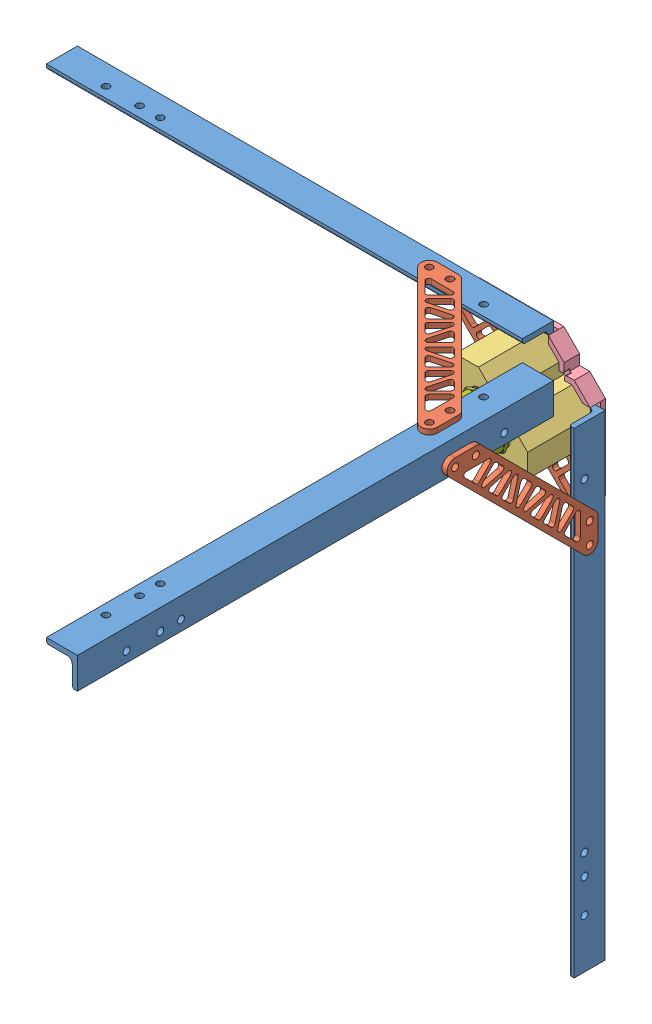
SolidWorks assembly Manifold Cage with struct Corner, configuration Default. Lengths in mm.
Overall size (327.03 327.03 327.03).
15 component instances, 9 part files, 15 mates.
Components (placement in the parent):
- L_Bar-1: L_Bar [8982K281] at (15.875 20.169 110.8643) x (0 1 0) z (0 0 1) size (19.05 19.05 292.1)
- StrucBracket_Universal-1: StrucBracket_Universal [Default] at (-18.6648 32.869 -22.8708) x (-0.707107 0 0.707107) z (0.707107 0 0.707107) size (19.05 3.17 126.81)
- L_Bar-2: L_Bar [8982K281] at (-152.4 20.169 -57.4107) x (0 0 -1) z (-1 0 0) size (19.05 19.05 292.1)
- StrucBracket_Universal-2: StrucBracket_Universal [Default] at (25.4 -14.3708 -22.8708) x (0 -0.707107 0.707107) z (0 0.707107 0.707107) size (19.05 3.17 126.81)
- StrucBracket_Universal-3: StrucBracket_Universal [Default] at (-18.6648 -14.3708 -70.1107) x (-0.707107 -0.707107 0) z (-0.707107 0.707107 0) size (19.05 3.17 126.81)
- L_Bar-3: L_Bar [8982K281] at (15.875 -148.106 -57.4107) x (1 0 0) z (0 -1 0) size (19.05 19.05 292.1)
- Subtractive Manifold with Cage-1: Subtractive Manifold with Cage [Default] at (5.6096 9.5657 -47.2855) x (0 1 0) z (-1 0 0) size (77.15 60.92 77.15)
  - Subtractive Manifold_V2-1: Subtractive Manifold_V2 [Default] at (-2.0967 -24.7998 2.4346) size (44.45 41.27 44.45)
  - Manifold Cage Lower-1: Manifold Cage Lower [Default] at (-27.4967 19.6502 27.8346) x (0 0 -1) z (-1 0 0) size (77.15 60.32 77.15)
  - Generic_8-32-1: Generic_8-32 [91251A194] at (-18.3833 -32.7373 18.7212) x (0.248031 -0.936462 0.248031) z (-0.707107 0 0.707107) size (6.86 6.86 17.41)
  - Valve Clip-1: Valve Clip [Default] at (-27.4967 26.9423 25.6017) x (0 -0.707107 0.707107) z (0 -0.707107 -0.707107) size (18.64 1 15.22)
  - Valve Clip-3: Valve Clip [Default] at (-25.2638 26.9423 28.8346) x (-0.707107 -0.707107 0) z (0.707107 -0.707107 0) size (18.64 1 15.22)
  - grainger-36x026-1: grainger-36x026 [Default] at (1.0783 -20.0967 13.5471) x (0 -1 0) z (-0.74066 0 0.67188) size (18.47 12.77 12.72)
  - grainger-36x026-2: grainger-36x026 [Default] at (-13.2092 -20.0967 -0.7404) x (0 -1 0) z (-0.958276 0 -0.285846) size (18.47 12.77 12.72)
  - Manifold Cage Upper-1: Manifold Cage Upper [Default] at (-10.9382 -27.9748 11.2761) x (0.707107 0 -0.707107) z (0.707107 0 0.707107) size (32.25 15.88 11.76)
Mates (geometry in assembly coordinates):
- Concentric3: concentric anti-aligned: cylinder of L_Bar-2 through (-57.15 16.994 -63.7607) axis (0 0 1) radius 2.1526; cylinder of StrucBracket_Universal-3 through (-57.15 16.994 -70.1107) axis (0 0 -1) radius 2.1526
- Concentric4: concentric anti-aligned: cylinder of L_Bar-2 through (-69.85 16.994 -63.7607) axis (0 0 1) radius 2.1526; cylinder of StrucBracket_Universal-3 through (-69.85 16.994 -70.1107) axis (0 0 -1) radius 2.1526
- Concentric5: concentric anti-aligned: cylinder of StrucBracket_Universal-3 through (12.7 -65.556 -70.1107) axis (0 0 -1) radius 2.1526; cylinder of L_Bar-3 through (12.7 -65.556 -63.7607) axis (0 0 1) radius 2.1526
- Coincident7: coincident anti-aligned: plane of StrucBracket_Universal-3 through (12.7 -52.856 -66.9357) normal (0 0 1); plane of L_Bar-3 through (6.35 -294.156 -66.9357) normal (0 0 -1)
- Concentric6: concentric aligned: cylinder of StrucBracket_Universal-2 through (25.4 -65.556 -54.2357) axis (-1 0 0) radius 2.1526; cylinder of L_Bar-3 through (22.225 -65.556 -54.2357) axis (-1 0 0) radius 2.1526
- Concentric7: concentric aligned: cylinder of StrucBracket_Universal-2 through (25.4 -52.856 -54.2357) axis (-1 0 0) radius 2.1526; cylinder of L_Bar-3 through (22.225 -52.856 -54.2357) axis (-1 0 0) radius 2.1526
- Concentric8: concentric aligned: cylinder of L_Bar-1 through (22.225 16.994 28.3143) axis (-1 0 0) radius 2.1526; cylinder of StrucBracket_Universal-2 through (25.4 16.994 28.3143) axis (-1 0 0) radius 2.1526
- Coincident8: coincident anti-aligned: plane of L_Bar-1 through (25.4 10.644 256.9143) normal (1 0 0); plane of StrucBracket_Universal-2 through (25.4 -52.856 -54.2357) normal (-1 0 0)
- Concentric9: concentric anti-aligned: cylinder of StrucBracket_Universal-1 through (-69.85 32.869 -54.2357) axis (0 1 0) radius 2.1526; cylinder of L_Bar-2 through (-69.85 26.519 -54.2357) axis (0 -1 0) radius 2.1526
- Concentric10: concentric anti-aligned: cylinder of StrucBracket_Universal-1 through (-57.15 32.869 -54.2357) axis (0 1 0) radius 2.1526; cylinder of L_Bar-2 through (-57.15 26.519 -54.2357) axis (0 -1 0) radius 2.1526
- Concentric11: concentric anti-aligned: cylinder of L_Bar-1 through (12.7 26.519 28.3143) axis (0 -1 0) radius 2.1526; cylinder of StrucBracket_Universal-1 through (12.7 32.869 28.3143) axis (0 1 0) radius 2.1526
- Coincident9: coincident anti-aligned: plane of L_Bar-1 through (25.4 29.694 256.9143) normal (0 1 0); plane of StrucBracket_Universal-1 through (-57.15 29.694 -54.2357) normal (0 -1 0)
- Coincident10: coincident anti-aligned: plane of L_Bar-3 through (19.05 -294.156 -63.7607) normal (0 0 1); plane of Subtractive Manifold with Cage-1/Subtractive Manifold_V2-1 through (3.175 7.469 -63.7607) normal (0 0 -1)
- Coincident11: coincident anti-aligned: plane of L_Bar-2 through (-298.45 26.519 -60.5857) normal (0 -1 0); plane of Subtractive Manifold with Cage-1/Subtractive Manifold_V2-1 through (-7.9375 26.519 -63.7607) normal (0 1 0)
- Coincident12: coincident anti-aligned: plane of L_Bar-3 through (22.225 -294.156 -49.4732) normal (-1 0 0); plane of Subtractive Manifold with Cage-1/Subtractive Manifold_V2-1 through (22.225 -3.6435 -63.7607) normal (1 0 0)
